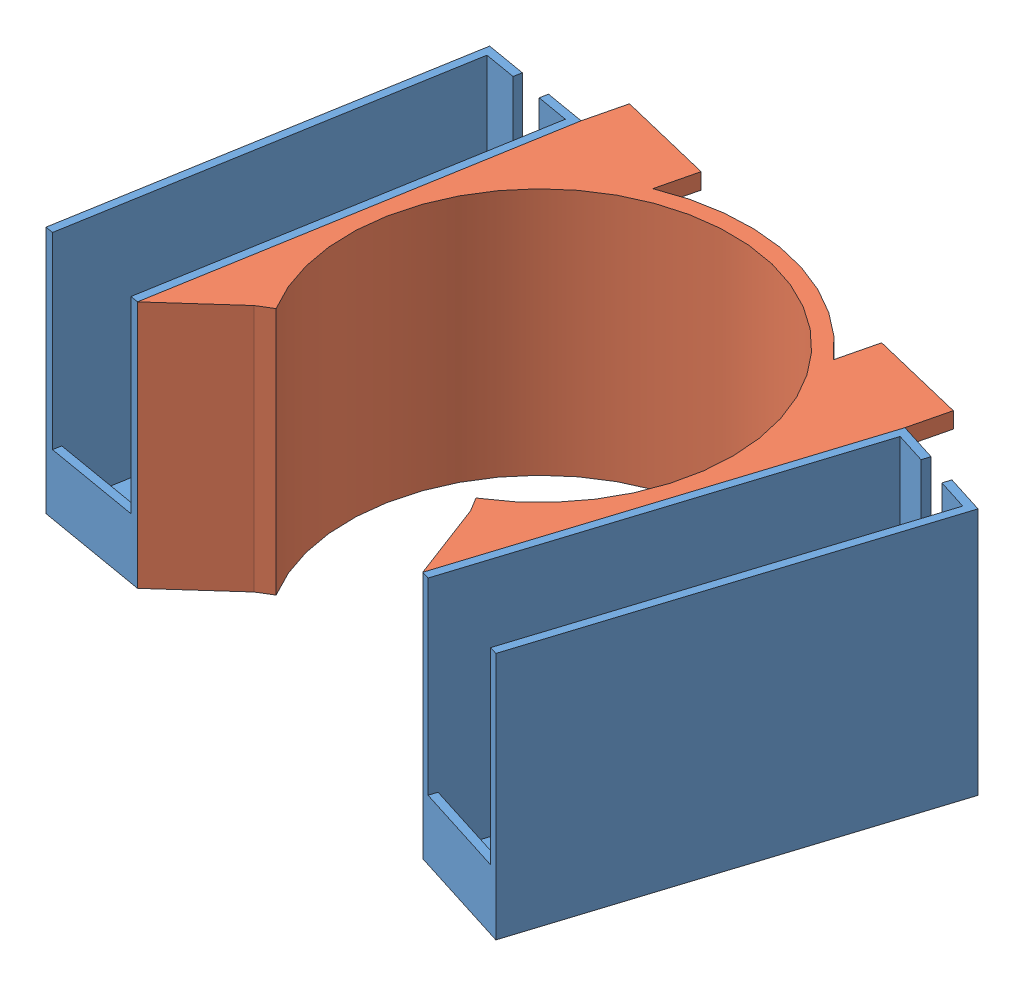
SolidWorks assembly Assem1, configuration Default. Lengths in mm.
Overall size (203.31 62 203.31).
3 component instances, 2 part files, 7 mates.
Components (placement in the parent):
- pi_holderSLDPRT-2: pi_holderSLDPRT [Default] at (306.8394 0 -94.9693) x (0.301629 0 -0.953425) z (0.953425 0 0.301629) size (96 62 28)
- pi_holderSLDPRT-3: pi_holderSLDPRT [Default] at (185.9808 0 -126.2825) x (0.169261 0 -0.985571) z (0.985571 0 0.169261) size (96 62 28)
- cycle-3: cycle [Default] at (245.7535 0 -167.1085) x (0.854007 0 -0.520262) z (0.520262 0 0.854007) size (147.94 62 147.94)
Mates (geometry in assembly coordinates):
- Coincident4: coincident anti-aligned: plane of pi_holderSLDPRT-2 through (280.1435 62 -103.4149) normal (-0.953425 0 -0.301629); plane of cycle-3 through (280.1435 62 -103.4149) normal (0.953425 0 0.301629)
- Coincident5: coincident aligned: line of pi_holderSLDPRT-2 through (280.1435 62 -103.4149) axis (0 -1 0); line of cycle-3 through (280.1435 62 -103.4149) axis (0 -1 0)
- Coincident7: coincident anti-aligned: plane of pi_holderSLDPRT-3 through (185.9808 62 -126.2825) normal (0.985571 0 0.169261); plane of cycle-3 through (185.9808 62 -126.2825) normal (-0.985571 0 -0.169261)
- Coincident8: coincident aligned: line of pi_holderSLDPRT-3 through (185.9808 62 -126.2825) axis (0 -1 0); line of cycle-3 through (185.9808 62 -126.2825) axis (0 -1 0)
- Coincident9: coincident anti-aligned: plane of pi_holderSLDPRT-2 through (306.8394 0 -94.9693) normal (0 -1 0)
- Coincident10: coincident anti-aligned: plane of cycle-3 through (245.7535 0 -167.1085) normal (0 -1 0)
- Coincident11: coincident anti-aligned: plane of pi_holderSLDPRT-3 through (185.9808 0 -126.2825) normal (0 -1 0)
